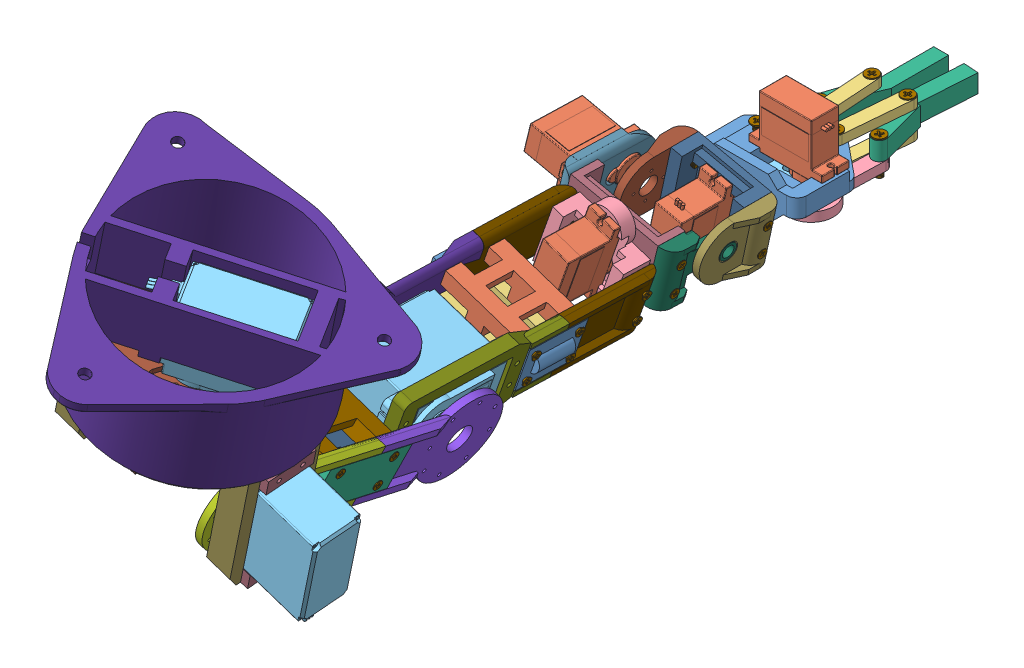
SolidWorks assembly Ensamblaje-Final, configuration Predeterminado. Lengths in mm.
Overall size (176.44 167.93 433.66).
101 component instances, 35 part files, 63 mates.
Components (placement in the parent):
- Base-De-Garra-1: Base-De-Garra [Predeterminado] at origin size (48.52 20 39)
- MG90S-Servo-1: MG90S-Servo [Default] at (7.6047 29.5 1.0784) x (1 0 0) z (0 0 -1) size (32.2 32.5 12.4)
- Conector-Garra1-1: Conector-Garra1 [Predeterminado] at (-7.2531 4 -30.2217) x (0.067723 0 0.997704) z (-0.997704 0 0.067723) size (35 4 6)
- Engranaje2-Garra-1: Engranaje2-Garra [Predeterminado] at (11.323 -8 -8.6731) x (0.999602 0 0.028201) z (-0.028201 0 0.999602) size (23.26 4 45.53)
- Engranaje-Garra-1: Engranaje-Garra [Predeterminado] at (-9.807 -8 -8.2268) x (0.997686 0 -0.067987) z (0.067987 0 0.997686) size (24.22 4 46.45)
- Pinza-Garra-1: Pinza-Garra [Predeterminado] at (-8.9078 -4 -48.9221) x (1 0 0.000251) z (-0.000251 0 1) size (14.5 8 47.96)
- Separador-Engrane-Base-1: Separador-Engrane-Base [Predeterminado] at (-10.9453 -4 0.7523) size (5.99 4 5.99)
- Soporte-Garra-1: Soporte-Garra [Predeterminado] at (0.5047 -4 -16.9902) x (1 0 0) z (0 0 1) size (25 4 6.56)
- Conector-Garra1-2: Conector-Garra1 [Predeterminado] at (-7.2531 -8 -30.2217) x (0.067723 0 0.997704) z (-0.997704 0 0.067723) size (35 4 6)
- Conector-Garra1-3: Conector-Garra1 [Predeterminado] at (8.9197 -8 -31.159) x (0.087453 0 -0.996169) z (0.996169 0 0.087453) size (35 4 6)
- Conector-Garra1-4: Conector-Garra1 [Predeterminado] at (8.9197 4 -31.159) x (0.087453 0 -0.996169) z (0.996169 0 0.087453) size (35 4 6)
- Pinza-Garra-2: Pinza-Garra [Predeterminado] at (11.0159 4 -48.7403) x (-0.997891 0 -0.064917) z (-0.064917 0 0.997891) size (14.5 8 47.96)
- flat head screw_am-1: flat head screw_am [B18.6.7M - M3 x 0.5 x 16 Type I Cross Recessed FHMS --16S] at (-6.9126 8.45 -45.273) x (0 -1 0) z (0 0 1) size (16 5.5 5.5)
- flat head screw_am-2: flat head screw_am [B18.6.7M - M3 x 0.5 x 16 Type I Cross Recessed FHMS --16S] at (-12.9169 4.45 -28.3045) x (0 -1 0) z (0 0 1) size (16 5.5 5.5)
- flat head screw_am-3: flat head screw_am [B18.6.7M - M3 x 0.5 x 16 Type I Cross Recessed FHMS --16S] at (-4.9453 8.45 -16.3416) x (0 -1 0) z (0 0 1) size (16 5.5 5.5)
- flat head screw_am-4: flat head screw_am [B18.6.7M - M3 x 0.5 x 16 Type I Cross Recessed FHMS --16S] at (6.2547 8.45 -16.3416) x (0 -1 0) z (0 0 1) size (16 5.5 5.5)
- flat head screw_am-5: flat head screw_am [B18.6.7M - M3 x 0.5 x 16 Type I Cross Recessed FHMS --16S] at (8.7872 8.45 -45.229) x (0 -1 0) z (0 0 1) size (16 5.5 5.5)
- flat head screw_am-6: flat head screw_am [B18.6.7M - M3 x 0.5 x 16 Type I Cross Recessed FHMS --16S] at (-10.9453 11.45 0.6284) x (0 -1 0) z (0 0 1) size (16 5.5 5.5)
- flat head screw_am-7: flat head screw_am [B18.6.7M - M3 x 0.5 x 16 Type I Cross Recessed FHMS --16S] at (13.6699 4.45 -27.9163) x (0 -1 0) z (-0.546944 0 0.837169) size (16 5.5 5.5)
- Ensamblaje-Eslabon5-1: Ensamblaje-Eslabon5 [Predeterminado] at (-1.5482 -3.196 23.8784) x (0.97745 -0.211168 0) z (-0.211168 -0.97745 0) size (45.34 36.4 35.5)
  - Eslabon5A-Servo-1: Eslabon5A-Servo [Predeterminado] at origin size (32.7 12 35.5)
  - Eslabon5B-1: Eslabon5B [Predeterminado] at (-16.1231 15.0816 -5.7351) x (0 1 0) z (0 0 1) size (31.65 6 24.89)
  - Eslabon5C-1: Eslabon5C [Predeterminado] at (16.5769 15.0816 -4.9919) x (0 1 0) z (0 0 -1) size (31.65 6 24.89)
  - MG90S-Servo-1: MG90S-Servo [Default] at (0.2252 27.75 -0.1146) x (0 0 -1) z (-1 0 0) size (32.2 32.5 12.4)
  - flat head screw_am-1: flat head screw_am [B18.6.7M - M2 x 0.4 x 13 Type I Cross Recessed FHMS --13S] at (-22.6064 6 -11.3635) x (1 0 0) z (0 0.146623 0.989192) size (13 3.8 3.8)
  - flat head screw_am-2: flat head screw_am [B18.6.7M - M2 x 0.4 x 13 Type I Cross Recessed FHMS --13S] at (-22.6064 6 0.6365) size (13 3.8 3.8)
  - flat head screw_am-3: flat head screw_am [B18.6.7M - M2 x 0.4 x 13 Type I Cross Recessed FHMS --13S] at (22.7349 6 0.6365) x (-1 0 0) z (0 -0.924225 -0.381849) size (13 3.8 3.8)
  - flat head screw_am-4: flat head screw_am [B18.6.7M - M2 x 0.4 x 13 Type I Cross Recessed FHMS --13S] at (22.7349 6 -11.3635) x (-1 0 0) z (0 -0.374285 -0.927314) size (13 3.8 3.8)
- Ensamblaje-Eslabon4-1: Ensamblaje-Eslabon4 [Predeterminado] at (-5.3609 2.9066 71.306) x (-0.97745 0.211168 0) z (-0.211024 -0.976781 0.036984) size (73.34 40.81 25.26)
  - Eslabon4A-1: Eslabon4A [Predeterminado] at origin size (39 12 25)
  - Eslabon4B-1: Eslabon4B [Predeterminado] at (20.4076 20.8175 -1.3719) x (0 1 0) z (0 0 -1) size (40.81 7.41 25.26)
  - Eslabon4C-1: Eslabon4C [Predeterminado] at (-18.5924 16.8477 -0.8514) x (0 1 0) z (0 0 1) size (33.2 6 24.95)
  - MG90S-Servo-1: MG90S-Servo [Default] at (48.4076 22.95 -1.248) x (0 1 0) z (0 0 1) size (32.2 32.5 12.4)
  - flat head screw_am-1: flat head screw_am [B18.6.7M - M2 x 0.4 x 13 Type I Cross Recessed FHMS --13S] at (-24.9349 6 -7.248) x (1 0 0) z (0 0.526224 0.850346) size (13 3.8 3.8)
  - flat head screw_am-2: flat head screw_am [B18.6.7M - M2 x 0.4 x 13 Type I Cross Recessed FHMS --13S] at (26.7489 6 -7.248) x (-1 0 0) z (0 0.689705 -0.724091) size (13 3.8 3.8)
  - flat head screw_am-3: flat head screw_am [B18.6.7M - M2 x 0.4 x 13 Type I Cross Recessed FHMS --13S] at (26.7489 6 4.752) x (-1 0 0) z (0 -0.924225 -0.381849) size (13 3.8 3.8)
  - flat head screw_am-4: flat head screw_am [B18.6.7M - M2 x 0.4 x 13 Type I Cross Recessed FHMS --13S] at (-24.9349 6 4.752) x (1 0 0) z (0 -0.35084 0.936436) size (13 3.8 3.8)
- Ensamblaje-Eslabon3-1: Ensamblaje-Eslabon3 [Predeterminado] at (-20.5255 -62.5515 181.4456) x (0.00781 0.03615 0.999316) z (0.311667 0.949479 -0.036783) size (122.83 52.95 40.95)
  - Eslabon3A-Servo-1: Eslabon3A-Servo [Predeterminado] at (-25.9252 12.8725 72.6169) size (72.49 6 30.8)
  - Eslabon3B-1: Eslabon3B [Predeterminado] at (-24.576 -19.8275 72.7083) x (-0.999999 0 -0.001206) z (-0.001206 0 0.999999) size (72.01 6.5 36)
  - Eslabon3C-1: Eslabon3C [Predeterminado] at (-76.6757 12.8725 72.8334) size (51.57 6.24 25.26)
  - Eslabon3D-1: Eslabon3D [Predeterminado] at (-57.913 15.8725 72.2662) x (0 0 -1) z (1 0 0) size (19 5.5 25.75)
  - Eslabon3E1-1: Eslabon3E1 [Predeterminado] at (-57.2515 -2.7343 81.6908) x (0 -1 0) z (0.999999 0 0.001206) size (32.7 11.9 26)
  - Eslabon3E2-1: Eslabon3E2 [Predeterminado] at (-57.2293 -4.2207 63.2908) x (0 1 0) z (0.999999 0 0.001206) size (32.7 6.5 26)
  - Eslabon3F-Servo-1: Eslabon3F-Servo [Predeterminado] at (-102.8295 -3.2506 77.8565) x (0 -1 0) z (0 0 1) size (32.7 12 35.5)
  - Eslabon3D-2: Eslabon3D [Predeterminado] at (-57.916 -22.8275 72.7669) x (-0.001206 0 0.999999) z (0.999999 0 0.001206) size (19 5.5 25.75)
  - Eslabon3C-2: Eslabon3C [Predeterminado] at (-76.668 -19.8275 72.177) x (0.999999 0 0.001206) z (0.001206 0 -0.999999) size (51.57 6.24 25.26)
  - MG90S-Servo-1: MG90S-Servo [Default] at (-75.0795 -3.4758 77.742) x (0 0 -1) z (0 1 0) size (32.2 32.5 12.4)
  - MG996R-Servo-1: MG996R-Servo [Default] at (-15.9295 -17.1275 72.4931) size (58.18 41.75 20)
  - flat head screw_am-1: flat head screw_am [B18.6.7M - M2 x 0.4 x 13 Type I Cross Recessed FHMS --13S] at (-96.815 -26.1887 66.4931) x (0 1 0) z (-0.54958 0 0.835441) size (13 3.8 3.8)
  - flat head screw_am-2: flat head screw_am [B18.6.7M - M2 x 0.4 x 13 Type I Cross Recessed FHMS --13S] at (-96.8295 -26.1887 78.4931) x (0 1 0) z (0 0 1) size (13 3.8 3.8)
  - flat head screw_am-3: flat head screw_am [B18.6.7M - M2 x 0.4 x 13 Type I Cross Recessed FHMS --13S] at (-67.4295 -26.1887 78.5285) x (0 1 0) z (0 0 1) size (13 3.8 3.8)
  - flat head screw_am-4: flat head screw_am [B18.6.7M - M2 x 0.4 x 13 Type I Cross Recessed FHMS --13S] at (-67.415 -26.1887 66.5286) x (0 1 0) z (0 0 1) size (13 3.8 3.8)
  - flat head screw_am-5: flat head screw_am [B18.6.7M - M2 x 0.4 x 13 Type I Cross Recessed FHMS --13S] at (-48.1895 -26.1887 78.5518) x (0 1 0) z (0 0 1) size (13 3.8 3.8)
  - flat head screw_am-6: flat head screw_am [B18.6.7M - M2 x 0.4 x 13 Type I Cross Recessed FHMS --13S] at (-48.1751 -26.1887 66.5518) x (0 1 0) z (0 0 1) size (13 3.8 3.8)
  - flat head screw_am-7: flat head screw_am [B18.6.7M - M2 x 0.4 x 13 Type I Cross Recessed FHMS --13S] at (-96.8295 20.0187 66.4931) x (0 -1 0) z (0 0 1) size (13 3.8 3.8)
  - flat head screw_am-8: flat head screw_am [B18.6.7M - M2 x 0.4 x 13 Type I Cross Recessed FHMS --13S] at (-96.8295 20.0187 78.4931) x (0 -1 0) z (0 0 1) size (13 3.8 3.8)
  - flat head screw_am-9: flat head screw_am [B18.6.7M - M2 x 0.4 x 13 Type I Cross Recessed FHMS --13S] at (-67.4195 20.0187 78.4931) x (0 -1 0) z (0 0 1) size (13 3.8 3.8)
  - flat head screw_am-10: flat head screw_am [B18.6.7M - M2 x 0.4 x 13 Type I Cross Recessed FHMS --13S] at (-67.4195 20.0187 66.4931) x (0 -1 0) z (-0.005668 0 0.999984) size (13 3.8 3.8)
  - flat head screw_am-11: flat head screw_am [B18.6.7M - M2 x 0.4 x 13 Type I Cross Recessed FHMS --13S] at (-48.1795 20.0187 66.4931) x (0 -1 0) z (0 0 1) size (13 3.8 3.8)
  - flat head screw_am-12: flat head screw_am [B18.6.7M - M2 x 0.4 x 13 Type I Cross Recessed FHMS --13S] at (-48.1795 20.0187 78.4931) x (0 -1 0) z (0 0 1) size (13 3.8 3.8)
  - flat head screw_am-13: flat head screw_am [B18.6.7M - M2 x 0.4 x 13 Type I Cross Recessed FHMS --13S] at (-48.2843 -3.4775 61.7857) x (-0.001206 0 0.999999) z (-0.925311 -0.379206 -0.001116) size (13 3.8 3.8)
  - flat head screw_am-14: flat head screw_am [B18.6.7M - M2 x 0.4 x 13 Type I Cross Recessed FHMS --13S] at (-67.4093 -3.4775 61.7626) x (-0.001206 0 0.999999) z (-0.925615 -0.378465 -0.001117) size (13 3.8 3.8)
- Ensamblaje-Eslabon2-1: Ensamblaje-Eslabon2 [Predeterminado] at (26.5522 -9.5437 186.8253) x (-0.298906 -0.907389 0.295468) z (0.088615 0.281893 0.955345) size (35.99 61.7 144)
  - Ensamblaje-Eslabon2AB-1: Ensamblaje-Eslabon2AB [Predeterminado] at origin size (35.99 13 144)
    - Agarre-Eslabon2AyB-1: Agarre-Eslabon2AyB [Predeterminado] at (-14.421 1.0451 41) size (18.5 3 41)
    - Eslabon2A-1: Eslabon2A [Predeterminado] at (-11.6524 -1.9549 75.4017) x (1 0 0) z (0 0 1) size (35.99 6 77)
    - Eslabon2B-1: Eslabon2B [Predeterminado] at (-11.1985 -1.9549 7.7213) x (-1 0 0) z (0 0 -1) size (35.99 6 77)
    - flat head screw_am-2: flat head screw_am [B18.6.7M - M2 x 0.4 x 13 Type I Cross Recessed FHMS --13S] at (-5.4254 4.3451 55.0617) x (0 -1 0) z (0.013375 0 0.999911) size (13 3.8 3.8)
    - flat head screw_am-3: flat head screw_am [B18.6.7M - M2 x 0.4 x 13 Type I Cross Recessed FHMS --13S] at (-17.425 4.3451 55.0617) x (0 -1 0) z (0 0 1) size (13 3.8 3.8)
    - flat head screw_am-4: flat head screw_am [B18.6.7M - M2 x 0.4 x 13 Type I Cross Recessed FHMS --13S] at (-17.4254 4.3451 28.0617) x (0 -1 0) z (0 0 1) size (13 3.8 3.8)
    - flat head screw_am-5: flat head screw_am [B18.6.7M - M2 x 0.4 x 13 Type I Cross Recessed FHMS --13S] at (-5.4254 4.3451 28.0617) x (0 -1 0) z (0 0 1) size (13 3.8 3.8)
  - Ensamblaje-Eslabon2AB-2: Ensamblaje-Eslabon2AB [Predeterminado] at (-22.8505 -53.0099 -0.0004) x (-1 0 0) z (0 0 1) size (35.99 13 144)
    - Agarre-Eslabon2AyB-1: Agarre-Eslabon2AyB [Predeterminado] at (-14.421 1.0451 41) size (18.5 3 41)
    - Eslabon2A-1: Eslabon2A [Predeterminado] at (-11.6524 -1.9549 75.4017) x (1 0 0) z (0 0 1) size (35.99 6 77)
    - Eslabon2B-1: Eslabon2B [Predeterminado] at (-11.1985 -1.9549 7.7213) x (-1 0 0) z (0 0 -1) size (35.99 6 77)
    - flat head screw_am-2: flat head screw_am [B18.6.7M - M2 x 0.4 x 13 Type I Cross Recessed FHMS --13S] at (-5.4254 4.3451 55.0617) x (0 -1 0) z (0.013375 0 0.999911) size (13 3.8 3.8)
    - flat head screw_am-3: flat head screw_am [B18.6.7M - M2 x 0.4 x 13 Type I Cross Recessed FHMS --13S] at (-17.425 4.3451 55.0617) x (0 -1 0) z (0 0 1) size (13 3.8 3.8)
    - flat head screw_am-4: flat head screw_am [B18.6.7M - M2 x 0.4 x 13 Type I Cross Recessed FHMS --13S] at (-17.4254 4.3451 28.0617) x (0 -1 0) z (0 0 1) size (13 3.8 3.8)
    - flat head screw_am-5: flat head screw_am [B18.6.7M - M2 x 0.4 x 13 Type I Cross Recessed FHMS --13S] at (-5.4254 4.3451 28.0617) x (0 -1 0) z (0 0 1) size (13 3.8 3.8)
  - Conexion-Eslabones2-1: Conexion-Eslabones2 [Predeterminado] at (-20.8254 -26.6184 42.469) x (0 0 1) z (0 1 0) size (35 11.9 49.1)
  - Conexion-Eslabones22-1: Conexion-Eslabones22 [Predeterminado] at (-8.9254 -26.6184 42.469) x (0 0 1) z (0 1 0) size (35 7 49.1)
  - flat head screw_am-2: flat head screw_am [B18.6.7M - M2 x 0.4 x 13 Type I Cross Recessed FHMS --13S] at (-1.6254 -26.5049 55.0614) x (-1 0 0) z (0 0 -1) size (13 3.8 3.8)
  - flat head screw_am-3: flat head screw_am [B18.6.7M - M2 x 0.4 x 13 Type I Cross Recessed FHMS --13S] at (-1.6254 -26.5049 28.0614) x (-1 0 0) z (0 0 -1) size (13 3.8 3.8)
- Ensamblaje-Eslabon1-1: Ensamblaje-Eslabon1 [Predeterminado] at (24.7861 74.9159 280.697) x (0.048773 0.136431 -0.989448) z (-0.950159 0.311741 -0.003851) size (85.98 66.64 110.6)
  - Tapa-Base-1: Tapa-Base [Predeterminado] at origin size (85.98 9.5 85.98)
  - Agarre-Servo1-1: Agarre-Servo1 [Predeterminado] at (0.9903 29.0045 27.1089) x (0 1 0) z (1 0 0) size (66.64 13 30.8)
  - Anclaje-Servo1-1: Anclaje-Servo1 [Predeterminado] at (-9.8767 2.5 -43.7911) x (1 0 0) z (0 -1 0) size (20 3.5 7)
  - Soporte-Tama-Servo-1: Soporte-Tama-Servo [Predeterminado] at (0.2471 31.4955 39.8089) x (0 1 0) z (-1 0 0) size (55.5 16.4 20.07)
  - Agarre-Servo1-2: Agarre-Servo1 [Predeterminado] at (-0.7438 29.0045 -27.5911) x (0 1 0) z (-1 0 0) size (66.64 13 30.8)
  - Anclaje-Servo1-2: Anclaje-Servo1 [Predeterminado] at (-9.8767 52 -43.7911) x (1 0 0) z (0 -1 0) size (20 3.5 7)
  - Anclaje-Servo1-3: Anclaje-Servo1 [Predeterminado] at (10.1233 10 39.8089) x (-1 0 0) z (0 1 0) size (20 3.5 7)
  - Anclaje-Servo1-4: Anclaje-Servo1 [Predeterminado] at (-9.8767 52 39.8089) x (1 0 0) z (0 -1 0) size (20 3.5 7)
  - MG996R-Servo-1: MG996R-Servo [Default] at (0.1233 32 -67.2911) x (0 1 0) z (1 0 0) size (58.18 41.75 20)
- flat head screw_am-10: flat head screw_am [B18.6.7M - M3 x 0.5 x 25 Type I Cross Recessed FHMS --25S] at (-26.0852 48.9299 274.4817) x (0.950159 -0.311741 0.003851) z (-0.002347 0.005202 0.999984) size (25 5.5 5.5)
- flat washer narrow_am-1: flat washer narrow_am [B18.22M - Plain washer, 3 mm, narrow] at (-7.8896 42.9601 274.5555) x (0.950159 -0.311741 0.003851) z (-0.073947 -0.213347 0.974174) size (0.9 7 7)
- flat washer narrow_am-3: flat washer narrow_am [B18.22M - Plain washer, 5 mm, narrow] at (-10.075 43.6771 274.5466) x (-0.950159 0.311741 -0.003851) z (0.004713 0.026715 0.999632) size (1.4 11 11)
- hex nut style 1_am-2: hex nut style 1_am [B18.2.4.1M - Hex nut, Style 1,  M3 x 0.5 --D-N] at (-5.6092 42.2119 274.5647) x (-0.014783 -0.057391 -0.998242) z (0.950159 -0.311741 0.003851) size (5.5 6.35 2.4)
- Ensamblaje-Base-1: Ensamblaje-Base [Predeterminado] at (41.8799 116.8683 282.4074) x (0.435733 -0.274711 0.857129) z (0.845765 -0.200822 -0.49432) size (118.64 44.96 111.67)
  - BaseBrazoMG995-1: BaseBrazoMG995 [Predeterminado] at origin size (118.64 44.96 111.67)
  - MG996R-Servo-1: MG996R-Servo [Default] at (3.0463 3 5.2102) x (0 0 -1) z (1 0 0) size (58.18 41.75 20)
Mates (geometry in assembly coordinates):
- Coincidente1: coincident: plane of Base-De-Garra-1 through (0 8 0) normal (0 1 0); plane of MG90S-Servo-1 through (7.6047 8 1.0784) normal (0 -1 0)
- Coincidente2: coincident: plane of Base-De-Garra-1 through (18.8547 4 -5.8216) normal (-1 0 0); plane of MG90S-Servo-1 through (18.8547 6.5 -4.9216) normal (1 0 0)
- Coincidente3: coincident: plane of Base-De-Garra-1 through (5.2547 4 7.0784) normal (0 0 -1); plane of MG90S-Servo-1 through (-3.8953 11 7.0784) normal (0 0 1)
- Coincidente4: coincident: plane of Base-De-Garra-1 through (-19.2453 0 14.6284) normal (0 -1 0); plane of Soporte-Garra-1 through (-5.1827 0 -15.3511) normal (0 1 0)
- Concéntrica4: concentric: cylinder of Base-De-Garra-1 through (-4.9453 4 -16.3416) axis (0 -1 0) radius 1.5; cylinder of Soporte-Garra-1 through (-4.9453 0 -16.3416) axis (0 -1 0) radius 1.5
- Concéntrica5: concentric: cylinder of Base-De-Garra-1 through (6.2547 4 -16.3416) axis (0 -1 0) radius 1.5; cylinder of Soporte-Garra-1 through (6.2547 0 -16.3416) axis (0 -1 0) radius 1.5
- Concéntrica6: concentric: cylinder of Base-De-Garra-1 through (-4.9453 4 -16.3416) axis (0 -1 0) radius 1.5; cylinder of Conector-Garra1-1 through (-4.9453 8 -16.3416) axis (0 -1 0) radius 1.5
- Coincidente5: coincident: plane of Base-De-Garra-1 through (-19.2453 4 14.6284) normal (0 1 0); plane of Conector-Garra1-1 through (-6.9092 4 -45.275) normal (0 -1 0)
- Coincidente7: coincident: plane of Engranaje-Garra-1 through (-9.807 -4 -8.2268) normal (0 1 0); plane of Separador-Engrane-Base-1 through (-10.9453 -4 0.6284) normal (0 -1 0)
- Concéntrica8: concentric: cylinder of Engranaje-Garra-1 through (-10.9453 -4 0.6284) axis (0 -1 0) radius 1.5; cylinder of Separador-Engrane-Base-1 through (-10.9453 0 0.6284) axis (0 -1 0) radius 1.4956
- Concéntrica9: concentric: cylinder of Base-De-Garra-1 through (-10.9453 4 0.6284) axis (0 -1 0) radius 1.5; cylinder of Engranaje-Garra-1 through (-10.9453 -4 0.6284) axis (0 -1 0) radius 1.5
- Coincidente8: coincident: plane of Base-De-Garra-1 through (-19.2453 0 14.6284) normal (0 -1 0); plane of Separador-Engrane-Base-1 through (-10.9453 0 0.6284) normal (0 1 0)
- Concéntrica11: concentric: cylinder of Conector-Garra1-1 through (-6.9126 8 -45.273) axis (0 -1 0) radius 1.4985; cylinder of Pinza-Garra-1 through (-6.9126 4 -45.273) axis (0 -1 0) radius 1.5
- Concéntrica12: concentric: cylinder of Engranaje-Garra-1 through (-12.9169 -4 -28.3045) axis (0 -1 0) radius 1.5; cylinder of Pinza-Garra-1 through (-12.9169 4 -28.3045) axis (0 -1 0) radius 1.5
- Coincidente9: coincident: plane of Pinza-Garra-1 through (-12.9132 -4 -28.3153) normal (0 -1 0); plane of Conector-Garra1-2 through (-6.9092 -4 -45.275) normal (0 1 0)
- Concéntrica13: concentric: cylinder of Pinza-Garra-1 through (-6.9126 4 -45.273) axis (0 -1 0) radius 1.5; cylinder of Conector-Garra1-2 through (-6.9126 -4 -45.273) axis (0 -1 0) radius 1.4985
- Concéntrica14: concentric: cylinder of Soporte-Garra-1 through (-4.9453 0 -16.3416) axis (0 -1 0) radius 1.5; cylinder of Conector-Garra1-2 through (-4.9453 -4 -16.3416) axis (0 -1 0) radius 1.5
- Concéntrica15: concentric: cylinder of Soporte-Garra-1 through (6.2547 0 -16.3416) axis (0 -1 0) radius 1.5; cylinder of Conector-Garra1-3 through (6.2547 -4 -16.3416) axis (0 -1 0) radius 1.4985
- Coincidente10: coincident: plane of Soporte-Garra-1 through (-5.1827 -4 -15.3511) normal (0 -1 0); plane of Conector-Garra1-3 through (6.251 -4 -16.3401) normal (0 1 0)
- Coincidente11: coincident: plane of Conector-Garra1-3 through (6.251 -4 -16.3401) normal (0 1 0); plane of Pinza-Garra-2 through (13.6699 -4 -27.9163) normal (0 -1 0)
- Concéntrica16: concentric: cylinder of Conector-Garra1-3 through (8.7872 -4 -45.229) axis (0 -1 0) radius 1.5; cylinder of Pinza-Garra-2 through (8.7872 -4 -45.229) axis (0 1 0) radius 1.5
- Concéntrica17: concentric: cylinder of Engranaje2-Garra-1 through (13.6729 -4 -27.9053) axis (0 -1 0) radius 1.4982; cylinder of Pinza-Garra-2 through (13.6729 -4 -27.9053) axis (0 1 0) radius 1.5
- Concéntrica18: concentric: cylinder of Conector-Garra1-4 through (8.7872 8 -45.229) axis (0 -1 0) radius 1.5; cylinder of Pinza-Garra-2 through (8.7872 -4 -45.229) axis (0 1 0) radius 1.5
- Coincidente12: coincident: plane of Conector-Garra1-4 through (6.251 4 -16.3401) normal (0 -1 0); plane of Pinza-Garra-2 through (13.6699 4 -27.9163) normal (0 1 0)
- Concéntrica19: concentric: cylinder of Base-De-Garra-1 through (6.2547 4 -16.3416) axis (0 -1 0) radius 1.5; cylinder of Conector-Garra1-4 through (6.2547 8 -16.3416) axis (0 -1 0) radius 1.4985
- Concéntrica20: concentric: cylinder of Conector-Garra1-1 through (-6.9126 8 -45.273) axis (0 -1 0) radius 1.4985; cone of flat head screw_am-1 through (-6.9126 8 -45.273) axis (0 -1 0)
- Concéntrica21: concentric: cylinder of Pinza-Garra-1 through (-12.9169 4 -28.3045) axis (0 -1 0) radius 1.5; cone of flat head screw_am-2 through (-12.9169 4 -28.3045) axis (0 -1 0)
- Concéntrica22: concentric: cylinder of Conector-Garra1-1 through (-4.9453 8 -16.3416) axis (0 -1 0) radius 1.5; cone of flat head screw_am-3 through (-4.9453 8 -16.3416) axis (0 -1 0)
- Concéntrica23: concentric: cylinder of Conector-Garra1-4 through (6.2547 8 -16.3416) axis (0 -1 0) radius 1.4985; cone of flat head screw_am-4 through (6.2547 8 -16.3416) axis (0 -1 0)
- Concéntrica24: concentric: cylinder of Conector-Garra1-4 through (8.7872 8 -45.229) axis (0 -1 0) radius 1.5; cone of flat head screw_am-5 through (8.7872 8 -45.229) axis (0 -1 0)
- Concéntrica25: concentric: cylinder of Base-De-Garra-1 through (-10.9453 4 0.6284) axis (0 -1 0) radius 1.5; cone of flat head screw_am-6 through (-10.9453 11 0.6284) axis (0 -1 0)
- Coincidente13: coincident: axis of Pinza-Garra-2 through (13.6699 -4 -27.9163) axis (0 1 0); axis of flat head screw_am-7 through (13.6699 -8.8893 -27.9163) axis (0 1 0)
- Coincidente14: coincident: plane of Pinza-Garra-2 through (13.6699 4 -27.9163) normal (0 1 0); circle of flat head screw_am-7
- Coincidente15: coincident: plane of Conector-Garra1-4 through (6.251 8 -16.3401) normal (0 1 0); circle of flat head screw_am-5
- Coincidente16: coincident: plane of Conector-Garra1-4 through (6.251 8 -16.3401) normal (0 1 0); circle of flat head screw_am-4
- Coincidente17: coincident: plane of Conector-Garra1-1 through (-6.9092 8 -45.275) normal (0 1 0); circle of flat head screw_am-1
- Coincidente18: coincident: plane of Conector-Garra1-1 through (-6.9092 8 -45.275) normal (0 1 0); circle of flat head screw_am-3
- Coincidente19: coincident: plane of MG90S-Servo-1 through (7.6047 11 1.0784) normal (0 1 0); circle of flat head screw_am-6
- Coincidente20: coincident: plane of Pinza-Garra-1 through (-12.9132 4 -28.3153) normal (0 1 0); circle of flat head screw_am-2
- Coincidente21: coincident: plane of Soporte-Garra-1 through (-5.1827 -4 -15.3511) normal (0 -1 0); plane of Conector-Garra1-2 through (-6.9092 -4 -45.275) normal (0 1 0)
- Concéntrica26: concentric: cylinder of MG90S-Servo-1 through (12.8547 -0.5 1.0784) axis (0 -1 0) radius 1.25; cylinder of Engranaje2-Garra-1 through (12.8547 -4 1.0784) axis (0 -1 0) radius 2.9962
- Coincidente24: coincident: plane of Engranaje2-Garra-1 through (8.5918 -4 -10.1273) normal (0 1 0); plane of Pinza-Garra-2 through (13.6699 -4 -27.9163) normal (0 -1 0)
- Coincidente25: coincident: axis of Base-De-Garra-1 through (-0.1953 2 15.1244) axis (0 0 1); axis of Ensamblaje-Eslabon5-1/Eslabon5A-Servo-1 through (-0.1953 2 26.8784) axis (0 0 -1)
- Coincidente26: coincident: plane of Base-De-Garra-1 through (-19.2453 4 19.1284) normal (0 0 1); plane of Ensamblaje-Eslabon5-1/MG90S-Servo-1 through (-0.1953 2 19.1284) normal (0 0 -1)
- Coincidente27: coincident: plane of Ensamblaje-Eslabon5-1/Eslabon5C-1 through (15.7876 -1.4534 43.0792) normal (-0.97745 0.211168 0); plane of Ensamblaje-Eslabon4-1/Eslabon4C-1 through (15.7876 -1.4534 43.0792) normal (0.97745 -0.211168 0)
- Concéntrica27: concentric: cylinder of Ensamblaje-Eslabon5-1/Eslabon5C-1 through (18.72 -2.0869 43.0792) axis (-0.97745 0.211168 0) radius 3.9994; cylinder of Ensamblaje-Eslabon4-1/Eslabon4C-1 through (15.7876 -1.4534 43.0792) axis (-0.97745 0.211168 0) radius 2.5
- Concéntrica28: concentric: cylinder of Ensamblaje-Eslabon4-1/Eslabon4A-1 through (-2.0984 3.3642 68.2619) axis (0.00781 0.03615 0.999316) radius 4; cylinder of Ensamblaje-Eslabon3-1/MG90S-Servo-1 through (-2.0554 3.563 73.7582) axis (-0.00781 -0.03615 -0.999316) radius 1.25
- Coincidente28: coincident: plane of Ensamblaje-Eslabon4-1/Eslabon4A-1 through (-5.3609 2.9066 71.306) normal (0.00781 0.03615 0.999316); plane of Ensamblaje-Eslabon3-1/MG90S-Servo-1 through (-2.0749 3.4726 71.2599) normal (-0.00781 -0.03615 -0.999316)
- Concéntrica29: concentric: cylinder of Ensamblaje-Eslabon3-1/Eslabon3B-1 through (-22.9707 14.3243 171.3564) axis (0.950159 -0.311741 0.003851) radius 5; cylinder of Ensamblaje-Eslabon2-1/Ensamblaje-Eslabon2AB-1/Eslabon2B-1 through (29.8581 -3.0085 171.5706) axis (-0.950159 0.311741 -0.003851) radius 5.4
- Coincidente29: coincident: plane of Ensamblaje-Eslabon3-1/Eslabon3B-1 through (-19.6438 13.2374 171.3745) normal (-0.950159 0.311741 -0.003851); plane of Ensamblaje-Eslabon2-1/Ensamblaje-Eslabon2AB-2/Eslabon2B-1 through (-19.6457 13.2317 171.3662) normal (0.950159 -0.311741 0.003851)
- Concéntrica30: concentric: circle of Ensamblaje-Eslabon2-1/Ensamblaje-Eslabon2AB-2/Eslabon2A-1; cylinder of Ensamblaje-Eslabon1-1/Soporte-Tama-Servo-1 through (-21.7619 47.5115 274.4993) axis (-0.950159 0.311741 -0.003851) radius 1.5
- Concéntrica31: concentric: cylinder of Ensamblaje-Eslabon2-1/Ensamblaje-Eslabon2AB-2/Eslabon2A-1 through (-12.9255 44.6123 274.5351) axis (0.950159 -0.311741 0.003851) radius 5.4; cylinder of Ensamblaje-Eslabon1-1/Soporte-Tama-Servo-1 through (-13.3055 44.737 274.5335) axis (-0.950159 0.311741 -0.003851) radius 10.0332
- Coincidente30: coincident: plane of Ensamblaje-Eslabon2-1/Ensamblaje-Eslabon2AB-2/Eslabon2A-1 through (-10.0747 43.6781 274.5501) normal (0.950159 -0.311741 0.003851); plane of Ensamblaje-Eslabon1-1/Soporte-Tama-Servo-1 through (-10.075 43.6771 274.5466) normal (0.950159 -0.311741 0.003851)
- Coincidente33: coincident: axis of Ensamblaje-Eslabon1-1/Soporte-Tama-Servo-1 through (-10.075 43.6771 274.5466) axis (-0.950159 0.311741 -0.003851); axis of flat head screw_am-10 through (-25.6576 48.7896 274.4835) axis (0.950159 -0.311741 0.003851)
- Coincidente34: coincident: plane of Ensamblaje-Eslabon1-1/Soporte-Tama-Servo-1 through (-22.7249 57.7439 275.7375) normal (-0.950159 0.311741 -0.003851); circle of flat head screw_am-10
- Coincidente35: coincident: axis of Ensamblaje-Eslabon1-1/Soporte-Tama-Servo-1 through (-10.075 43.6771 274.5466) axis (-0.950159 0.311741 -0.003851); axis of flat washer narrow_am-1 through (-7.8896 42.9601 274.5555) axis (-0.950159 0.311741 -0.003851)
- Concéntrica32: concentric: cylinder of Ensamblaje-Eslabon1-1/Soporte-Tama-Servo-1 through (-21.7619 47.5115 274.4993) axis (-0.950159 0.311741 -0.003851) radius 1.5; cylinder of flat washer narrow_am-3 through (23.1093 32.7896 274.6811) axis (0.950159 -0.311741 0.003851) radius 2.89
- Coincidente37: coincident: plane of Ensamblaje-Eslabon1-1/Soporte-Tama-Servo-1 through (-10.075 43.6771 274.5466) normal (0.950159 -0.311741 0.003851); plane of flat washer narrow_am-3 through (-10.9759 40.9322 274.6242) normal (-0.950159 0.311741 -0.003851)
- Coincidente38: coincident: plane of flat washer narrow_am-1 through (-7.6847 46.4813 275.3422) normal (-0.950159 0.311741 -0.003851); plane of flat washer narrow_am-3 through (-10.4593 38.0168 274.6997) normal (0.950159 -0.311741 0.003851)
- Coincidente39: coincident: plane of flat washer narrow_am-1 through (-7.3323 44.6638 274.9709) normal (0.950159 -0.311741 0.003851); plane of hex nut style 1_am-2 through (-7.8083 43.2757 280.0458) normal (-0.950159 0.311741 -0.003851)
- Coincidente40: coincident: axis of Ensamblaje-Eslabon1-1/Soporte-Tama-Servo-1 through (-10.075 43.6771 274.5466) axis (-0.950159 0.311741 -0.003851); axis of hex nut style 1_am-2 through (-6.1339 42.3841 274.5626) axis (0.950159 -0.311741 0.003851)
- Coincidente41: coincident: axis of Ensamblaje-Eslabon1-1/Tapa-Base-1 through (24.2408 72.5057 280.2436) axis (0.307926 0.940321 0.144836); axis of Ensamblaje-Base-1/BaseBrazoMG995-1 through (25.6265 76.7371 280.8953) axis (0.307926 0.940321 0.144836)
- Coincidente42: coincident: plane of Ensamblaje-Eslabon1-1/Tapa-Base-1 through (24.7861 74.9159 280.697) normal (0.307926 0.940321 0.144836); plane of Ensamblaje-Base-1/BaseBrazoMG995-1 through (25.0107 74.8565 280.6056) normal (-0.307926 -0.940321 -0.144836)
